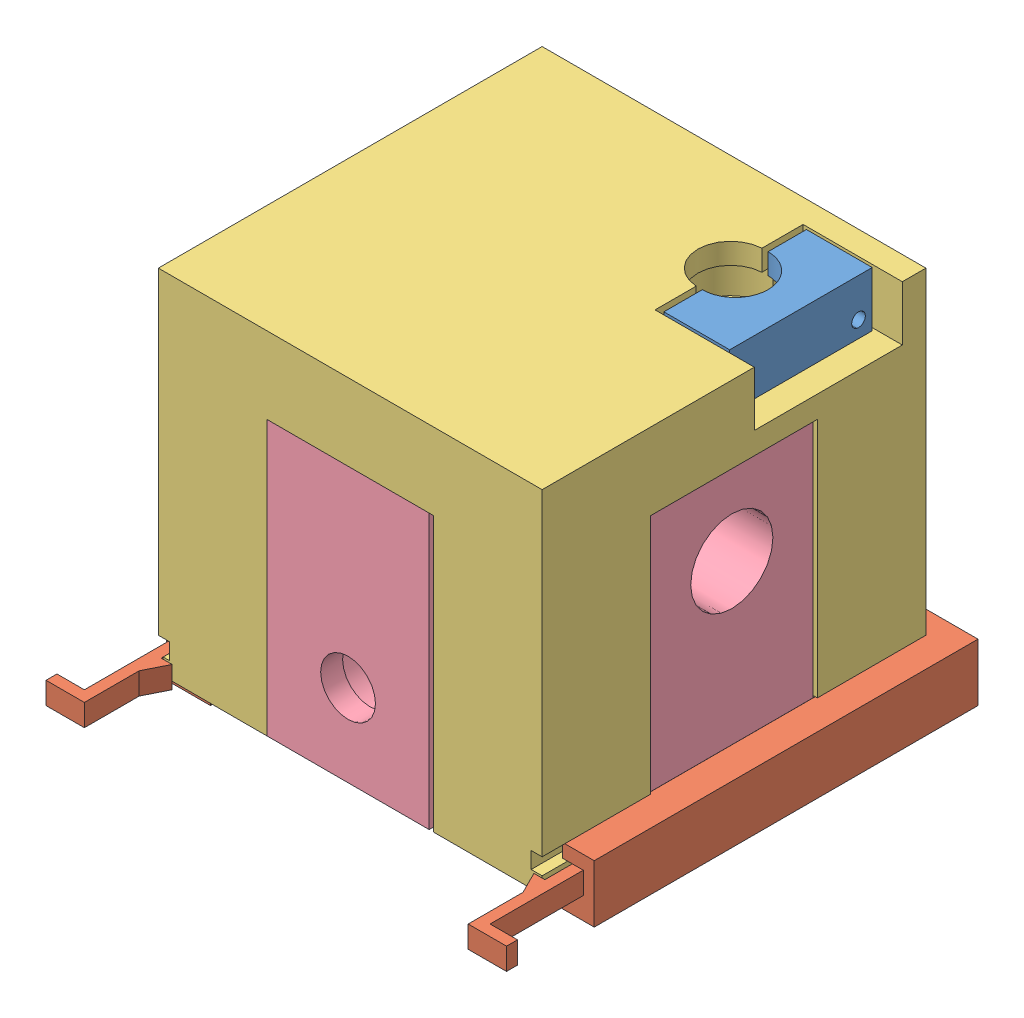
SolidWorks assembly P3DMIPC-Tête_complete, configuration Défaut. Lengths in mm.
Overall size (94 69 96.37).
4 component instances, 4 part files, 3 mates.
Components (placement in the parent):
- P3DMIPC-Clip_Buse_E3D-1: P3DMIPC-Clip_Buse_E3D [Défaut] at (17.0518 23.4109 40.0035) x (1 0 0) z (0 1 0) size (12 26 10)
- P3DMIPC-Clip_tête-1: P3DMIPC-Clip_tête [Défaut] at (26.9018 -25.0891 4.5597) x (1 0 0) z (0 -1 0) size (84 89 10.5)
- P3DMIPC-Porte_Buse_E3DX1-1: P3DMIPC-Porte_Buse_E3DX1 [Défaut] at (22.03 33.4019 79.1927) x (0 0 1) z (0 -1 0) size (70 70 64)
- P3DMIPC-Chariot-1: P3DMIPC-Chariot [Défaut] at (-48.37 -30.5981 79.1927) size (94 50 94)
Mates (geometry in assembly coordinates):
- Coïncidente19: coincident anti-aligned: plane of P3DMIPC-Porte_Buse_E3DX1-1 through (22.03 19.4019 79.1927) normal (0 -1 0); plane of P3DMIPC-Chariot-1 through (21.63 19.4019 79.1927) normal (0 1 0)
- Coïncidente20: coincident anti-aligned: plane of P3DMIPC-Porte_Buse_E3DX1-1 through (-28.17 19.4019 79.1927) normal (1 0 0); plane of P3DMIPC-Chariot-1 through (-28.17 19.4019 79.1927) normal (-1 0 0)
- Coïncidente21: coincident aligned: plane of P3DMIPC-Porte_Buse_E3DX1-1 through (22.03 -30.5981 79.1927) normal (0 0 1); plane of P3DMIPC-Chariot-1 through (21.63 -30.5981 79.1927) normal (0 0 1)
